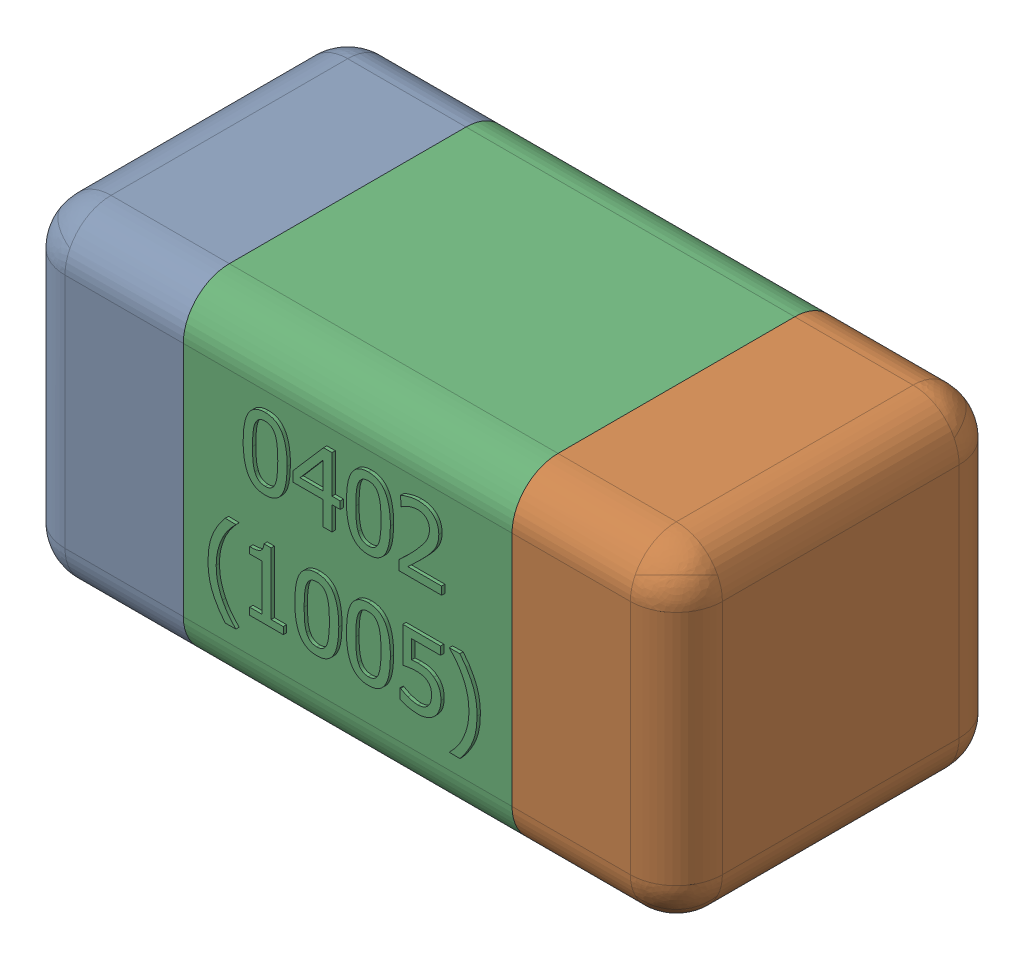
SolidWorks assembly C13, configuration Standard. Lengths in mm.
Overall size (1.01 0.51 0.51).
4 component instances, 3 part files, 0 mates.
Components (placement in the parent):
- C13-subassembly-1-1: C13-subassembly-1 [Standard] at (6.7251 -11.2048 0) x (1 0 0) z (0 0 1) size (1.01 0.51 0.51)
  - User Library-0402_Cap-1: User Library-0402_Cap [Standard] at origin size (0.26 0.51 0.51)
  - User Library-0402_Cap-1-1: User Library-0402_Cap-1 [Standard] at origin size (0.26 0.5 0.51)
  - User Library-0402_Cap-2-1: User Library-0402_Cap-2 [Standard] at origin size (0.5 0.5 0.51)
